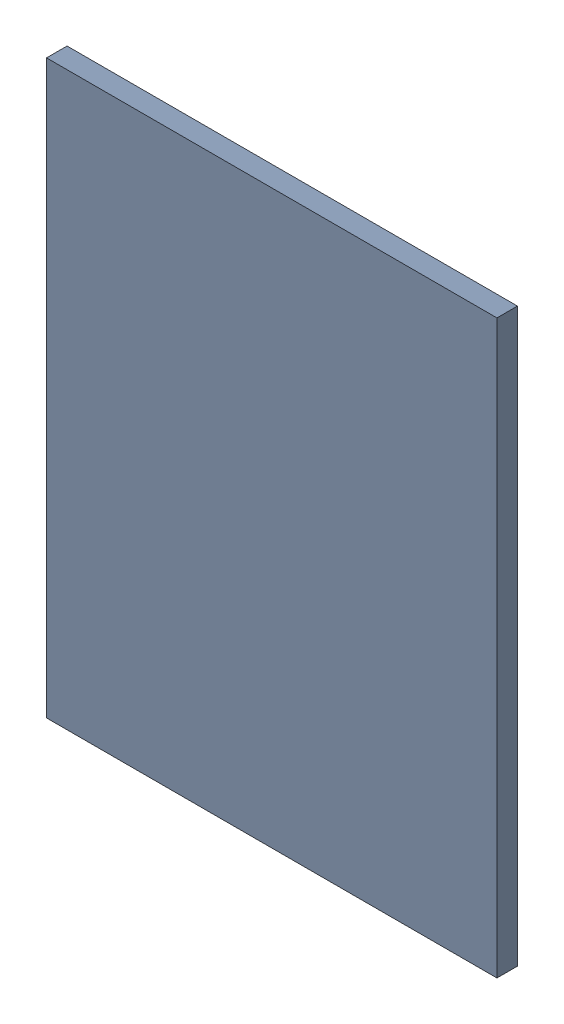
SolidWorks assembly Pad C2-1(29.2mm,43.5mm) on Top Layer, configuration Predeterminado. Lengths in mm.
Overall size (0.78 0.99 0.04).
2 component instances, 1 part files, 0 mates.
Components (placement in the parent):
- Pad C2-1(29.2mm,43.5mm) on Top Layer-1-1: Pad C2-1(29.2mm,43.5mm) on Top Layer-1 [Predeterminado] at (-68.317 -44.187 -0.0457) size (0.78 0.99 0.04)
  - Pad C2-1(29.2mm,43.5mm) on Top Layer-Part-1-1: Pad C2-1(29.2mm,43.5mm) on Top Layer-Part-1 [Predeterminado] at origin size (0.78 0.99 0.04)
